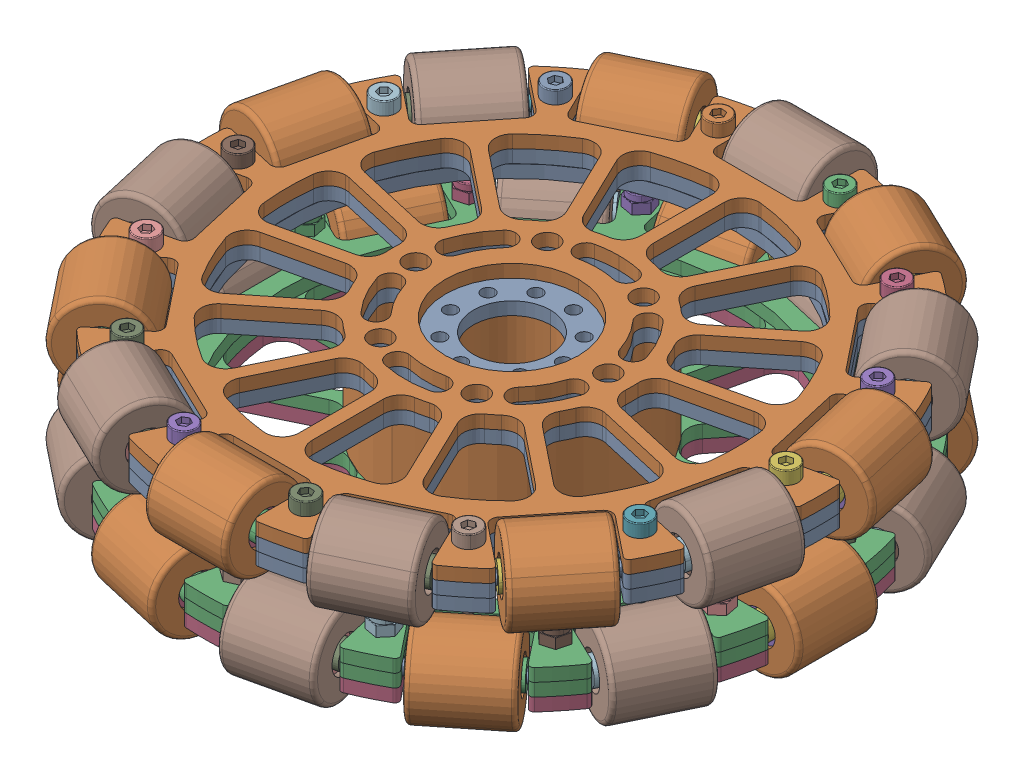
SolidWorks assembly 南京理工大学Alliance航发全向轮装配V2.STEP, configuration 默认. Lengths in mm.
Overall size (201.18 51.02 200.87).
259 component instances, 10 part files, 0 mates.
Components (placement in the parent):
- 南京理工大学Alliance航发小滚子装配.STEP-1: 南京理工大学Alliance航发小滚子装配.STEP [默认] at (-12.75 1.5 67) x (0 -0.970891 0.239524) z (0 0.239524 0.970891) size (24.07 25.5 24.07)
  - 南京理工大学Alliance销钉M3x25.5.STEP-1: 南京理工大学Alliance销钉M3x25.5.STEP [默认] at origin size (3 25.5 3)
  - 南京理工大学Alliance白色滚子.STEP-1: 南京理工大学Alliance白色滚子.STEP [默认] at (0 3.25 0) x (0.94776 0 0.318984) z (-0.318984 0 0.94776) size (19 19 19)
  - 南京理工大学Alliance垫片3x6x2.STEP-1: 南京理工大学Alliance垫片3x6x2.STEP [默认] at (0 20.85 0) size (6 2 6)
  - 南京理工大学Alliance轴承3x8x4.STEP-1: 南京理工大学Alliance轴承3x8x4.STEP [默认] at (0 16.85 0) size (8 4 8)
  - 南京理工大学Alliance轴承3x8x4.STEP-2: 南京理工大学Alliance轴承3x8x4.STEP [默认] at (0 4.65 0) size (8 4 8)
  - 南京理工大学Alliance垫片3x6x2.STEP-2: 南京理工大学Alliance垫片3x6x2.STEP [默认] at (0 2.65 0) size (6 2 6)
- 南京理工大学Alliance航发小滚子装配.STEP-2: 南京理工大学Alliance航发小滚子装配.STEP [默认] at (2.4786 -18.5 68.1573) x (-0.189674 -0.52291 -0.831017) z (0.116358 -0.852388 0.509799) size (24.07 25.5 24.07)
  - 南京理工大学Alliance销钉M3x25.5.STEP-1: 南京理工大学Alliance销钉M3x25.5.STEP [默认] at origin size (3 25.5 3)
  - 南京理工大学Alliance白色滚子.STEP-1: 南京理工大学Alliance白色滚子.STEP [默认] at (0 3.25 0) x (0.94776 0 0.318984) z (-0.318984 0 0.94776) size (19 19 19)
  - 南京理工大学Alliance垫片3x6x2.STEP-1: 南京理工大学Alliance垫片3x6x2.STEP [默认] at (0 20.85 0) size (6 2 6)
  - 南京理工大学Alliance轴承3x8x4.STEP-1: 南京理工大学Alliance轴承3x8x4.STEP [默认] at (0 16.85 0) size (8 4 8)
  - 南京理工大学Alliance轴承3x8x4.STEP-2: 南京理工大学Alliance轴承3x8x4.STEP [默认] at (0 4.65 0) size (8 4 8)
  - 南京理工大学Alliance垫片3x6x2.STEP-2: 南京理工大学Alliance垫片3x6x2.STEP [默认] at (0 2.65 0) size (6 2 6)
- 南京理工大学Alliance航发小滚子装配.STEP-3: 南京理工大学Alliance航发小滚子装配.STEP [默认] at (-27.3392 -18.5 62.483) x (0.189674 -0.52291 -0.831017) z (-0.116358 -0.852388 0.509799) size (24.07 25.5 24.07)
  - 南京理工大学Alliance销钉M3x25.5.STEP-1: 南京理工大学Alliance销钉M3x25.5.STEP [默认] at origin size (3 25.5 3)
  - 南京理工大学Alliance白色滚子.STEP-1: 南京理工大学Alliance白色滚子.STEP [默认] at (0 3.25 0) x (0.94776 0 0.318984) z (-0.318984 0 0.94776) size (19 19 19)
  - 南京理工大学Alliance垫片3x6x2.STEP-1: 南京理工大学Alliance垫片3x6x2.STEP [默认] at (0 20.85 0) size (6 2 6)
  - 南京理工大学Alliance轴承3x8x4.STEP-1: 南京理工大学Alliance轴承3x8x4.STEP [默认] at (0 16.85 0) size (8 4 8)
  - 南京理工大学Alliance轴承3x8x4.STEP-2: 南京理工大学Alliance轴承3x8x4.STEP [默认] at (0 4.65 0) size (8 4 8)
  - 南京理工大学Alliance垫片3x6x2.STEP-2: 南京理工大学Alliance垫片3x6x2.STEP [默认] at (0 2.65 0) size (6 2 6)
- 南京理工大学Alliance航发小滚子装配.STEP-4: 南京理工大学Alliance航发小滚子装配.STEP [默认] at (-51.7422 -18.5 44.4332) x (0.531455 -0.52291 -0.666424) z (-0.326029 -0.852388 0.408827) size (24.07 25.5 24.07)
  - 南京理工大学Alliance销钉M3x25.5.STEP-1: 南京理工大学Alliance销钉M3x25.5.STEP [默认] at origin size (3 25.5 3)
  - 南京理工大学Alliance白色滚子.STEP-1: 南京理工大学Alliance白色滚子.STEP [默认] at (0 3.25 0) x (0.94776 0 0.318984) z (-0.318984 0 0.94776) size (19 19 19)
  - 南京理工大学Alliance垫片3x6x2.STEP-1: 南京理工大学Alliance垫片3x6x2.STEP [默认] at (0 20.85 0) size (6 2 6)
  - 南京理工大学Alliance轴承3x8x4.STEP-1: 南京理工大学Alliance轴承3x8x4.STEP [默认] at (0 16.85 0) size (8 4 8)
  - 南京理工大学Alliance轴承3x8x4.STEP-2: 南京理工大学Alliance轴承3x8x4.STEP [默认] at (0 4.65 0) size (8 4 8)
  - 南京理工大学Alliance垫片3x6x2.STEP-2: 南京理工大学Alliance垫片3x6x2.STEP [默认] at (0 2.65 0) size (6 2 6)
- 南京理工大学Alliance航发小滚子装配.STEP-5: 南京理工大学Alliance航发小滚子装配.STEP [默认] at (-65.8969 -18.5 17.5829) x (0.767975 -0.52291 -0.369837) z (-0.471125 -0.852388 0.226882) size (24.07 25.5 24.07)
  - 南京理工大学Alliance销钉M3x25.5.STEP-1: 南京理工大学Alliance销钉M3x25.5.STEP [默认] at origin size (3 25.5 3)
  - 南京理工大学Alliance白色滚子.STEP-1: 南京理工大学Alliance白色滚子.STEP [默认] at (0 3.25 0) x (0.94776 0 0.318984) z (-0.318984 0 0.94776) size (19 19 19)
  - 南京理工大学Alliance垫片3x6x2.STEP-1: 南京理工大学Alliance垫片3x6x2.STEP [默认] at (0 20.85 0) size (6 2 6)
  - 南京理工大学Alliance轴承3x8x4.STEP-1: 南京理工大学Alliance轴承3x8x4.STEP [默认] at (0 16.85 0) size (8 4 8)
  - 南京理工大学Alliance轴承3x8x4.STEP-2: 南京理工大学Alliance轴承3x8x4.STEP [默认] at (0 4.65 0) size (8 4 8)
  - 南京理工大学Alliance垫片3x6x2.STEP-2: 南京理工大学Alliance垫片3x6x2.STEP [默认] at (0 2.65 0) size (6 2 6)
- 南京理工大学Alliance航发小滚子装配.STEP-6: 南京理工大学Alliance航发小滚子装配.STEP [默认] at (-67 -18.5 -12.75) x (0.852388 -0.52291 0) z (-0.52291 -0.852388 0) size (24.07 25.5 24.07)
  - 南京理工大学Alliance销钉M3x25.5.STEP-1: 南京理工大学Alliance销钉M3x25.5.STEP [默认] at origin size (3 25.5 3)
  - 南京理工大学Alliance白色滚子.STEP-1: 南京理工大学Alliance白色滚子.STEP [默认] at (0 3.25 0) x (0.94776 0 0.318984) z (-0.318984 0 0.94776) size (19 19 19)
  - 南京理工大学Alliance垫片3x6x2.STEP-1: 南京理工大学Alliance垫片3x6x2.STEP [默认] at (0 20.85 0) size (6 2 6)
  - 南京理工大学Alliance轴承3x8x4.STEP-1: 南京理工大学Alliance轴承3x8x4.STEP [默认] at (0 16.85 0) size (8 4 8)
  - 南京理工大学Alliance轴承3x8x4.STEP-2: 南京理工大学Alliance轴承3x8x4.STEP [默认] at (0 4.65 0) size (8 4 8)
  - 南京理工大学Alliance垫片3x6x2.STEP-2: 南京理工大学Alliance垫片3x6x2.STEP [默认] at (0 2.65 0) size (6 2 6)
- 南京理工大学Alliance航发小滚子装配.STEP-7: 南京理工大学Alliance航发小滚子装配.STEP [默认] at (-54.8329 -18.5 -40.5576) x (0.767975 -0.52291 0.369837) z (-0.471125 -0.852388 -0.226882) size (24.07 25.5 24.07)
  - 南京理工大学Alliance销钉M3x25.5.STEP-1: 南京理工大学Alliance销钉M3x25.5.STEP [默认] at origin size (3 25.5 3)
  - 南京理工大学Alliance白色滚子.STEP-1: 南京理工大学Alliance白色滚子.STEP [默认] at (0 3.25 0) x (0.94776 0 0.318984) z (-0.318984 0 0.94776) size (19 19 19)
  - 南京理工大学Alliance垫片3x6x2.STEP-1: 南京理工大学Alliance垫片3x6x2.STEP [默认] at (0 20.85 0) size (6 2 6)
  - 南京理工大学Alliance轴承3x8x4.STEP-1: 南京理工大学Alliance轴承3x8x4.STEP [默认] at (0 16.85 0) size (8 4 8)
  - 南京理工大学Alliance轴承3x8x4.STEP-2: 南京理工大学Alliance轴承3x8x4.STEP [默认] at (0 4.65 0) size (8 4 8)
  - 南京理工大学Alliance垫片3x6x2.STEP-2: 南京理工大学Alliance垫片3x6x2.STEP [默认] at (0 2.65 0) size (6 2 6)
- 南京理工大学Alliance航发小滚子装配.STEP-8: 南京理工大学Alliance航发小滚子装配.STEP [默认] at (-31.8055 -18.5 -60.3322) x (0.531455 -0.52291 0.666424) z (-0.326029 -0.852388 -0.408827) size (24.07 25.5 24.07)
  - 南京理工大学Alliance销钉M3x25.5.STEP-1: 南京理工大学Alliance销钉M3x25.5.STEP [默认] at origin size (3 25.5 3)
  - 南京理工大学Alliance白色滚子.STEP-1: 南京理工大学Alliance白色滚子.STEP [默认] at (0 3.25 0) x (0.94776 0 0.318984) z (-0.318984 0 0.94776) size (19 19 19)
  - 南京理工大学Alliance垫片3x6x2.STEP-1: 南京理工大学Alliance垫片3x6x2.STEP [默认] at (0 20.85 0) size (6 2 6)
  - 南京理工大学Alliance轴承3x8x4.STEP-1: 南京理工大学Alliance轴承3x8x4.STEP [默认] at (0 16.85 0) size (8 4 8)
  - 南京理工大学Alliance轴承3x8x4.STEP-2: 南京理工大学Alliance轴承3x8x4.STEP [默认] at (0 4.65 0) size (8 4 8)
  - 南京理工大学Alliance垫片3x6x2.STEP-2: 南京理工大学Alliance垫片3x6x2.STEP [默认] at (0 2.65 0) size (6 2 6)
- 南京理工大学Alliance航发小滚子装配.STEP-9: 南京理工大学Alliance航发小滚子装配.STEP [默认] at (-2.4786 -18.5 -68.1573) x (0.189674 -0.52291 0.831017) z (-0.116358 -0.852388 -0.509799) size (24.07 25.5 24.07)
  - 南京理工大学Alliance销钉M3x25.5.STEP-1: 南京理工大学Alliance销钉M3x25.5.STEP [默认] at origin size (3 25.5 3)
  - 南京理工大学Alliance白色滚子.STEP-1: 南京理工大学Alliance白色滚子.STEP [默认] at (0 3.25 0) x (0.94776 0 0.318984) z (-0.318984 0 0.94776) size (19 19 19)
  - 南京理工大学Alliance垫片3x6x2.STEP-1: 南京理工大学Alliance垫片3x6x2.STEP [默认] at (0 20.85 0) size (6 2 6)
  - 南京理工大学Alliance轴承3x8x4.STEP-1: 南京理工大学Alliance轴承3x8x4.STEP [默认] at (0 16.85 0) size (8 4 8)
  - 南京理工大学Alliance轴承3x8x4.STEP-2: 南京理工大学Alliance轴承3x8x4.STEP [默认] at (0 4.65 0) size (8 4 8)
  - 南京理工大学Alliance垫片3x6x2.STEP-2: 南京理工大学Alliance垫片3x6x2.STEP [默认] at (0 2.65 0) size (6 2 6)
- 南京理工大学Alliance航发小滚子装配.STEP-10: 南京理工大学Alliance航发小滚子装配.STEP [默认] at (27.3392 -18.5 -62.483) x (-0.189674 -0.52291 0.831017) z (0.116358 -0.852388 -0.509799) size (24.07 25.5 24.07)
  - 南京理工大学Alliance销钉M3x25.5.STEP-1: 南京理工大学Alliance销钉M3x25.5.STEP [默认] at origin size (3 25.5 3)
  - 南京理工大学Alliance白色滚子.STEP-1: 南京理工大学Alliance白色滚子.STEP [默认] at (0 3.25 0) x (0.94776 0 0.318984) z (-0.318984 0 0.94776) size (19 19 19)
  - 南京理工大学Alliance垫片3x6x2.STEP-1: 南京理工大学Alliance垫片3x6x2.STEP [默认] at (0 20.85 0) size (6 2 6)
  - 南京理工大学Alliance轴承3x8x4.STEP-1: 南京理工大学Alliance轴承3x8x4.STEP [默认] at (0 16.85 0) size (8 4 8)
  - 南京理工大学Alliance轴承3x8x4.STEP-2: 南京理工大学Alliance轴承3x8x4.STEP [默认] at (0 4.65 0) size (8 4 8)
  - 南京理工大学Alliance垫片3x6x2.STEP-2: 南京理工大学Alliance垫片3x6x2.STEP [默认] at (0 2.65 0) size (6 2 6)
- 南京理工大学Alliance航发小滚子装配.STEP-11: 南京理工大学Alliance航发小滚子装配.STEP [默认] at (51.7422 -18.5 -44.4332) x (-0.531455 -0.52291 0.666424) z (0.326029 -0.852388 -0.408827) size (24.07 25.5 24.07)
  - 南京理工大学Alliance销钉M3x25.5.STEP-1: 南京理工大学Alliance销钉M3x25.5.STEP [默认] at origin size (3 25.5 3)
  - 南京理工大学Alliance白色滚子.STEP-1: 南京理工大学Alliance白色滚子.STEP [默认] at (0 3.25 0) x (0.94776 0 0.318984) z (-0.318984 0 0.94776) size (19 19 19)
  - 南京理工大学Alliance垫片3x6x2.STEP-1: 南京理工大学Alliance垫片3x6x2.STEP [默认] at (0 20.85 0) size (6 2 6)
  - 南京理工大学Alliance轴承3x8x4.STEP-1: 南京理工大学Alliance轴承3x8x4.STEP [默认] at (0 16.85 0) size (8 4 8)
  - 南京理工大学Alliance轴承3x8x4.STEP-2: 南京理工大学Alliance轴承3x8x4.STEP [默认] at (0 4.65 0) size (8 4 8)
  - 南京理工大学Alliance垫片3x6x2.STEP-2: 南京理工大学Alliance垫片3x6x2.STEP [默认] at (0 2.65 0) size (6 2 6)
- 南京理工大学Alliance航发小滚子装配.STEP-12: 南京理工大学Alliance航发小滚子装配.STEP [默认] at (65.8969 -18.5 -17.5829) x (-0.767975 -0.52291 0.369837) z (0.471125 -0.852388 -0.226882) size (24.07 25.5 24.07)
  - 南京理工大学Alliance销钉M3x25.5.STEP-1: 南京理工大学Alliance销钉M3x25.5.STEP [默认] at origin size (3 25.5 3)
  - 南京理工大学Alliance白色滚子.STEP-1: 南京理工大学Alliance白色滚子.STEP [默认] at (0 3.25 0) x (0.94776 0 0.318984) z (-0.318984 0 0.94776) size (19 19 19)
  - 南京理工大学Alliance垫片3x6x2.STEP-1: 南京理工大学Alliance垫片3x6x2.STEP [默认] at (0 20.85 0) size (6 2 6)
  - 南京理工大学Alliance轴承3x8x4.STEP-1: 南京理工大学Alliance轴承3x8x4.STEP [默认] at (0 16.85 0) size (8 4 8)
  - 南京理工大学Alliance轴承3x8x4.STEP-2: 南京理工大学Alliance轴承3x8x4.STEP [默认] at (0 4.65 0) size (8 4 8)
  - 南京理工大学Alliance垫片3x6x2.STEP-2: 南京理工大学Alliance垫片3x6x2.STEP [默认] at (0 2.65 0) size (6 2 6)
- 南京理工大学Alliance航发小滚子装配.STEP-13: 南京理工大学Alliance航发小滚子装配.STEP [默认] at (67 -18.5 12.75) x (-0.852388 -0.52291 0) z (0.52291 -0.852388 0) size (24.07 25.5 24.07)
  - 南京理工大学Alliance销钉M3x25.5.STEP-1: 南京理工大学Alliance销钉M3x25.5.STEP [默认] at origin size (3 25.5 3)
  - 南京理工大学Alliance白色滚子.STEP-1: 南京理工大学Alliance白色滚子.STEP [默认] at (0 3.25 0) x (0.94776 0 0.318984) z (-0.318984 0 0.94776) size (19 19 19)
  - 南京理工大学Alliance垫片3x6x2.STEP-1: 南京理工大学Alliance垫片3x6x2.STEP [默认] at (0 20.85 0) size (6 2 6)
  - 南京理工大学Alliance轴承3x8x4.STEP-1: 南京理工大学Alliance轴承3x8x4.STEP [默认] at (0 16.85 0) size (8 4 8)
  - 南京理工大学Alliance轴承3x8x4.STEP-2: 南京理工大学Alliance轴承3x8x4.STEP [默认] at (0 4.65 0) size (8 4 8)
  - 南京理工大学Alliance垫片3x6x2.STEP-2: 南京理工大学Alliance垫片3x6x2.STEP [默认] at (0 2.65 0) size (6 2 6)
- 南京理工大学Alliance航发小滚子装配.STEP-14: 南京理工大学Alliance航发小滚子装配.STEP [默认] at (54.8329 -18.5 40.5576) x (-0.767975 -0.52291 -0.369837) z (0.471125 -0.852388 0.226882) size (24.07 25.5 24.07)
  - 南京理工大学Alliance销钉M3x25.5.STEP-1: 南京理工大学Alliance销钉M3x25.5.STEP [默认] at origin size (3 25.5 3)
  - 南京理工大学Alliance白色滚子.STEP-1: 南京理工大学Alliance白色滚子.STEP [默认] at (0 3.25 0) x (0.94776 0 0.318984) z (-0.318984 0 0.94776) size (19 19 19)
  - 南京理工大学Alliance垫片3x6x2.STEP-1: 南京理工大学Alliance垫片3x6x2.STEP [默认] at (0 20.85 0) size (6 2 6)
  - 南京理工大学Alliance轴承3x8x4.STEP-1: 南京理工大学Alliance轴承3x8x4.STEP [默认] at (0 16.85 0) size (8 4 8)
  - 南京理工大学Alliance轴承3x8x4.STEP-2: 南京理工大学Alliance轴承3x8x4.STEP [默认] at (0 4.65 0) size (8 4 8)
  - 南京理工大学Alliance垫片3x6x2.STEP-2: 南京理工大学Alliance垫片3x6x2.STEP [默认] at (0 2.65 0) size (6 2 6)
- 南京理工大学Alliance航发小滚子装配.STEP-15: 南京理工大学Alliance航发小滚子装配.STEP [默认] at (31.8055 -18.5 60.3322) x (-0.531455 -0.52291 -0.666424) z (0.326029 -0.852388 0.408827) size (24.07 25.5 24.07)
  - 南京理工大学Alliance销钉M3x25.5.STEP-1: 南京理工大学Alliance销钉M3x25.5.STEP [默认] at origin size (3 25.5 3)
  - 南京理工大学Alliance白色滚子.STEP-1: 南京理工大学Alliance白色滚子.STEP [默认] at (0 3.25 0) x (0.94776 0 0.318984) z (-0.318984 0 0.94776) size (19 19 19)
  - 南京理工大学Alliance垫片3x6x2.STEP-1: 南京理工大学Alliance垫片3x6x2.STEP [默认] at (0 20.85 0) size (6 2 6)
  - 南京理工大学Alliance轴承3x8x4.STEP-1: 南京理工大学Alliance轴承3x8x4.STEP [默认] at (0 16.85 0) size (8 4 8)
  - 南京理工大学Alliance轴承3x8x4.STEP-2: 南京理工大学Alliance轴承3x8x4.STEP [默认] at (0 4.65 0) size (8 4 8)
  - 南京理工大学Alliance垫片3x6x2.STEP-2: 南京理工大学Alliance垫片3x6x2.STEP [默认] at (0 2.65 0) size (6 2 6)
- 南京理工大学Alliance航发小滚子装配.STEP-16: 南京理工大学Alliance航发小滚子装配.STEP [默认] at (-40.5576 1.5 54.8329) x (-0.103925 -0.970891 0.215803) z (-0.421254 0.239524 0.874742) size (24.07 25.5 24.07)
  - 南京理工大学Alliance销钉M3x25.5.STEP-1: 南京理工大学Alliance销钉M3x25.5.STEP [默认] at origin size (3 25.5 3)
  - 南京理工大学Alliance白色滚子.STEP-1: 南京理工大学Alliance白色滚子.STEP [默认] at (0 3.25 0) x (0.94776 0 0.318984) z (-0.318984 0 0.94776) size (19 19 19)
  - 南京理工大学Alliance垫片3x6x2.STEP-1: 南京理工大学Alliance垫片3x6x2.STEP [默认] at (0 20.85 0) size (6 2 6)
  - 南京理工大学Alliance轴承3x8x4.STEP-1: 南京理工大学Alliance轴承3x8x4.STEP [默认] at (0 16.85 0) size (8 4 8)
  - 南京理工大学Alliance轴承3x8x4.STEP-2: 南京理工大学Alliance轴承3x8x4.STEP [默认] at (0 4.65 0) size (8 4 8)
  - 南京理工大学Alliance垫片3x6x2.STEP-2: 南京理工大学Alliance垫片3x6x2.STEP [默认] at (0 2.65 0) size (6 2 6)
- 南京理工大学Alliance航发小滚子装配.STEP-17: 南京理工大学Alliance航发小滚子装配.STEP [默认] at (-60.3322 1.5 31.8055) x (-0.187267 -0.970891 0.14934) z (-0.759073 0.239524 0.60534) size (24.07 25.5 24.07)
  - 南京理工大学Alliance销钉M3x25.5.STEP-1: 南京理工大学Alliance销钉M3x25.5.STEP [默认] at origin size (3 25.5 3)
  - 南京理工大学Alliance白色滚子.STEP-1: 南京理工大学Alliance白色滚子.STEP [默认] at (0 3.25 0) x (0.94776 0 0.318984) z (-0.318984 0 0.94776) size (19 19 19)
  - 南京理工大学Alliance垫片3x6x2.STEP-1: 南京理工大学Alliance垫片3x6x2.STEP [默认] at (0 20.85 0) size (6 2 6)
  - 南京理工大学Alliance轴承3x8x4.STEP-1: 南京理工大学Alliance轴承3x8x4.STEP [默认] at (0 16.85 0) size (8 4 8)
  - 南京理工大学Alliance轴承3x8x4.STEP-2: 南京理工大学Alliance轴承3x8x4.STEP [默认] at (0 4.65 0) size (8 4 8)
  - 南京理工大学Alliance垫片3x6x2.STEP-2: 南京理工大学Alliance垫片3x6x2.STEP [默认] at (0 2.65 0) size (6 2 6)
- 南京理工大学Alliance航发小滚子装配.STEP-18: 南京理工大学Alliance航发小滚子装配.STEP [默认] at (-68.1573 1.5 2.4786) x (-0.233518 -0.970891 0.053299) z (-0.946548 0.239524 0.216043) size (24.07 25.5 24.07)
  - 南京理工大学Alliance销钉M3x25.5.STEP-1: 南京理工大学Alliance销钉M3x25.5.STEP [默认] at origin size (3 25.5 3)
  - 南京理工大学Alliance白色滚子.STEP-1: 南京理工大学Alliance白色滚子.STEP [默认] at (0 3.25 0) x (0.94776 0 0.318984) z (-0.318984 0 0.94776) size (19 19 19)
  - 南京理工大学Alliance垫片3x6x2.STEP-1: 南京理工大学Alliance垫片3x6x2.STEP [默认] at (0 20.85 0) size (6 2 6)
  - 南京理工大学Alliance轴承3x8x4.STEP-1: 南京理工大学Alliance轴承3x8x4.STEP [默认] at (0 16.85 0) size (8 4 8)
  - 南京理工大学Alliance轴承3x8x4.STEP-2: 南京理工大学Alliance轴承3x8x4.STEP [默认] at (0 4.65 0) size (8 4 8)
  - 南京理工大学Alliance垫片3x6x2.STEP-2: 南京理工大学Alliance垫片3x6x2.STEP [默认] at (0 2.65 0) size (6 2 6)
- 南京理工大学Alliance航发小滚子装配.STEP-19: 南京理工大学Alliance航发小滚子装配.STEP [默认] at (-62.483 1.5 -27.3392) x (-0.233518 -0.970891 -0.053299) z (-0.946548 0.239524 -0.216043) size (24.07 25.5 24.07)
  - 南京理工大学Alliance销钉M3x25.5.STEP-1: 南京理工大学Alliance销钉M3x25.5.STEP [默认] at origin size (3 25.5 3)
  - 南京理工大学Alliance白色滚子.STEP-1: 南京理工大学Alliance白色滚子.STEP [默认] at (0 3.25 0) x (0.94776 0 0.318984) z (-0.318984 0 0.94776) size (19 19 19)
  - 南京理工大学Alliance垫片3x6x2.STEP-1: 南京理工大学Alliance垫片3x6x2.STEP [默认] at (0 20.85 0) size (6 2 6)
  - 南京理工大学Alliance轴承3x8x4.STEP-1: 南京理工大学Alliance轴承3x8x4.STEP [默认] at (0 16.85 0) size (8 4 8)
  - 南京理工大学Alliance轴承3x8x4.STEP-2: 南京理工大学Alliance轴承3x8x4.STEP [默认] at (0 4.65 0) size (8 4 8)
  - 南京理工大学Alliance垫片3x6x2.STEP-2: 南京理工大学Alliance垫片3x6x2.STEP [默认] at (0 2.65 0) size (6 2 6)
- 南京理工大学Alliance航发小滚子装配.STEP-20: 南京理工大学Alliance航发小滚子装配.STEP [默认] at (-44.4332 1.5 -51.7422) x (-0.187267 -0.970891 -0.14934) z (-0.759073 0.239524 -0.60534) size (24.07 25.5 24.07)
  - 南京理工大学Alliance销钉M3x25.5.STEP-1: 南京理工大学Alliance销钉M3x25.5.STEP [默认] at origin size (3 25.5 3)
  - 南京理工大学Alliance白色滚子.STEP-1: 南京理工大学Alliance白色滚子.STEP [默认] at (0 3.25 0) x (0.94776 0 0.318984) z (-0.318984 0 0.94776) size (19 19 19)
  - 南京理工大学Alliance垫片3x6x2.STEP-1: 南京理工大学Alliance垫片3x6x2.STEP [默认] at (0 20.85 0) size (6 2 6)
  - 南京理工大学Alliance轴承3x8x4.STEP-1: 南京理工大学Alliance轴承3x8x4.STEP [默认] at (0 16.85 0) size (8 4 8)
  - 南京理工大学Alliance轴承3x8x4.STEP-2: 南京理工大学Alliance轴承3x8x4.STEP [默认] at (0 4.65 0) size (8 4 8)
  - 南京理工大学Alliance垫片3x6x2.STEP-2: 南京理工大学Alliance垫片3x6x2.STEP [默认] at (0 2.65 0) size (6 2 6)
- 南京理工大学Alliance航发小滚子装配.STEP-21: 南京理工大学Alliance航发小滚子装配.STEP [默认] at (-17.5829 1.5 -65.8969) x (-0.103925 -0.970891 -0.215803) z (-0.421254 0.239524 -0.874742) size (24.07 25.5 24.07)
  - 南京理工大学Alliance销钉M3x25.5.STEP-1: 南京理工大学Alliance销钉M3x25.5.STEP [默认] at origin size (3 25.5 3)
  - 南京理工大学Alliance白色滚子.STEP-1: 南京理工大学Alliance白色滚子.STEP [默认] at (0 3.25 0) x (0.94776 0 0.318984) z (-0.318984 0 0.94776) size (19 19 19)
  - 南京理工大学Alliance垫片3x6x2.STEP-1: 南京理工大学Alliance垫片3x6x2.STEP [默认] at (0 20.85 0) size (6 2 6)
  - 南京理工大学Alliance轴承3x8x4.STEP-1: 南京理工大学Alliance轴承3x8x4.STEP [默认] at (0 16.85 0) size (8 4 8)
  - 南京理工大学Alliance轴承3x8x4.STEP-2: 南京理工大学Alliance轴承3x8x4.STEP [默认] at (0 4.65 0) size (8 4 8)
  - 南京理工大学Alliance垫片3x6x2.STEP-2: 南京理工大学Alliance垫片3x6x2.STEP [默认] at (0 2.65 0) size (6 2 6)
- 南京理工大学Alliance航发小滚子装配.STEP-22: 南京理工大学Alliance航发小滚子装配.STEP [默认] at (12.75 1.5 -67) x (0 -0.970891 -0.239524) z (0 0.239524 -0.970891) size (24.07 25.5 24.07)
  - 南京理工大学Alliance销钉M3x25.5.STEP-1: 南京理工大学Alliance销钉M3x25.5.STEP [默认] at origin size (3 25.5 3)
  - 南京理工大学Alliance白色滚子.STEP-1: 南京理工大学Alliance白色滚子.STEP [默认] at (0 3.25 0) x (0.94776 0 0.318984) z (-0.318984 0 0.94776) size (19 19 19)
  - 南京理工大学Alliance垫片3x6x2.STEP-1: 南京理工大学Alliance垫片3x6x2.STEP [默认] at (0 20.85 0) size (6 2 6)
  - 南京理工大学Alliance轴承3x8x4.STEP-1: 南京理工大学Alliance轴承3x8x4.STEP [默认] at (0 16.85 0) size (8 4 8)
  - 南京理工大学Alliance轴承3x8x4.STEP-2: 南京理工大学Alliance轴承3x8x4.STEP [默认] at (0 4.65 0) size (8 4 8)
  - 南京理工大学Alliance垫片3x6x2.STEP-2: 南京理工大学Alliance垫片3x6x2.STEP [默认] at (0 2.65 0) size (6 2 6)
- 南京理工大学Alliance航发小滚子装配.STEP-23: 南京理工大学Alliance航发小滚子装配.STEP [默认] at (40.5576 1.5 -54.8329) x (0.103925 -0.970891 -0.215803) z (0.421254 0.239524 -0.874742) size (24.07 25.5 24.07)
  - 南京理工大学Alliance销钉M3x25.5.STEP-1: 南京理工大学Alliance销钉M3x25.5.STEP [默认] at origin size (3 25.5 3)
  - 南京理工大学Alliance白色滚子.STEP-1: 南京理工大学Alliance白色滚子.STEP [默认] at (0 3.25 0) x (0.94776 0 0.318984) z (-0.318984 0 0.94776) size (19 19 19)
  - 南京理工大学Alliance垫片3x6x2.STEP-1: 南京理工大学Alliance垫片3x6x2.STEP [默认] at (0 20.85 0) size (6 2 6)
  - 南京理工大学Alliance轴承3x8x4.STEP-1: 南京理工大学Alliance轴承3x8x4.STEP [默认] at (0 16.85 0) size (8 4 8)
  - 南京理工大学Alliance轴承3x8x4.STEP-2: 南京理工大学Alliance轴承3x8x4.STEP [默认] at (0 4.65 0) size (8 4 8)
  - 南京理工大学Alliance垫片3x6x2.STEP-2: 南京理工大学Alliance垫片3x6x2.STEP [默认] at (0 2.65 0) size (6 2 6)
- 南京理工大学Alliance航发小滚子装配.STEP-24: 南京理工大学Alliance航发小滚子装配.STEP [默认] at (60.3322 1.5 -31.8055) x (0.187267 -0.970891 -0.14934) z (0.759073 0.239524 -0.60534) size (24.07 25.5 24.07)
  - 南京理工大学Alliance销钉M3x25.5.STEP-1: 南京理工大学Alliance销钉M3x25.5.STEP [默认] at origin size (3 25.5 3)
  - 南京理工大学Alliance白色滚子.STEP-1: 南京理工大学Alliance白色滚子.STEP [默认] at (0 3.25 0) x (0.94776 0 0.318984) z (-0.318984 0 0.94776) size (19 19 19)
  - 南京理工大学Alliance垫片3x6x2.STEP-1: 南京理工大学Alliance垫片3x6x2.STEP [默认] at (0 20.85 0) size (6 2 6)
  - 南京理工大学Alliance轴承3x8x4.STEP-1: 南京理工大学Alliance轴承3x8x4.STEP [默认] at (0 16.85 0) size (8 4 8)
  - 南京理工大学Alliance轴承3x8x4.STEP-2: 南京理工大学Alliance轴承3x8x4.STEP [默认] at (0 4.65 0) size (8 4 8)
  - 南京理工大学Alliance垫片3x6x2.STEP-2: 南京理工大学Alliance垫片3x6x2.STEP [默认] at (0 2.65 0) size (6 2 6)
- 南京理工大学Alliance航发小滚子装配.STEP-25: 南京理工大学Alliance航发小滚子装配.STEP [默认] at (68.1573 1.5 -2.4786) x (0.233518 -0.970891 -0.053299) z (0.946548 0.239524 -0.216043) size (24.07 25.5 24.07)
  - 南京理工大学Alliance销钉M3x25.5.STEP-1: 南京理工大学Alliance销钉M3x25.5.STEP [默认] at origin size (3 25.5 3)
  - 南京理工大学Alliance白色滚子.STEP-1: 南京理工大学Alliance白色滚子.STEP [默认] at (0 3.25 0) x (0.94776 0 0.318984) z (-0.318984 0 0.94776) size (19 19 19)
  - 南京理工大学Alliance垫片3x6x2.STEP-1: 南京理工大学Alliance垫片3x6x2.STEP [默认] at (0 20.85 0) size (6 2 6)
  - 南京理工大学Alliance轴承3x8x4.STEP-1: 南京理工大学Alliance轴承3x8x4.STEP [默认] at (0 16.85 0) size (8 4 8)
  - 南京理工大学Alliance轴承3x8x4.STEP-2: 南京理工大学Alliance轴承3x8x4.STEP [默认] at (0 4.65 0) size (8 4 8)
  - 南京理工大学Alliance垫片3x6x2.STEP-2: 南京理工大学Alliance垫片3x6x2.STEP [默认] at (0 2.65 0) size (6 2 6)
- 南京理工大学Alliance航发小滚子装配.STEP-26: 南京理工大学Alliance航发小滚子装配.STEP [默认] at (62.483 1.5 27.3392) x (0.233518 -0.970891 0.053299) z (0.946548 0.239524 0.216043) size (24.07 25.5 24.07)
  - 南京理工大学Alliance销钉M3x25.5.STEP-1: 南京理工大学Alliance销钉M3x25.5.STEP [默认] at origin size (3 25.5 3)
  - 南京理工大学Alliance白色滚子.STEP-1: 南京理工大学Alliance白色滚子.STEP [默认] at (0 3.25 0) x (0.94776 0 0.318984) z (-0.318984 0 0.94776) size (19 19 19)
  - 南京理工大学Alliance垫片3x6x2.STEP-1: 南京理工大学Alliance垫片3x6x2.STEP [默认] at (0 20.85 0) size (6 2 6)
  - 南京理工大学Alliance轴承3x8x4.STEP-1: 南京理工大学Alliance轴承3x8x4.STEP [默认] at (0 16.85 0) size (8 4 8)
  - 南京理工大学Alliance轴承3x8x4.STEP-2: 南京理工大学Alliance轴承3x8x4.STEP [默认] at (0 4.65 0) size (8 4 8)
  - 南京理工大学Alliance垫片3x6x2.STEP-2: 南京理工大学Alliance垫片3x6x2.STEP [默认] at (0 2.65 0) size (6 2 6)
- 南京理工大学Alliance航发小滚子装配.STEP-27: 南京理工大学Alliance航发小滚子装配.STEP [默认] at (44.4332 1.5 51.7422) x (0.187267 -0.970891 0.14934) z (0.759073 0.239524 0.60534) size (24.07 25.5 24.07)
  - 南京理工大学Alliance销钉M3x25.5.STEP-1: 南京理工大学Alliance销钉M3x25.5.STEP [默认] at origin size (3 25.5 3)
  - 南京理工大学Alliance白色滚子.STEP-1: 南京理工大学Alliance白色滚子.STEP [默认] at (0 3.25 0) x (0.94776 0 0.318984) z (-0.318984 0 0.94776) size (19 19 19)
  - 南京理工大学Alliance垫片3x6x2.STEP-1: 南京理工大学Alliance垫片3x6x2.STEP [默认] at (0 20.85 0) size (6 2 6)
  - 南京理工大学Alliance轴承3x8x4.STEP-1: 南京理工大学Alliance轴承3x8x4.STEP [默认] at (0 16.85 0) size (8 4 8)
  - 南京理工大学Alliance轴承3x8x4.STEP-2: 南京理工大学Alliance轴承3x8x4.STEP [默认] at (0 4.65 0) size (8 4 8)
  - 南京理工大学Alliance垫片3x6x2.STEP-2: 南京理工大学Alliance垫片3x6x2.STEP [默认] at (0 2.65 0) size (6 2 6)
- 南京理工大学Alliance航发小滚子装配.STEP-28: 南京理工大学Alliance航发小滚子装配.STEP [默认] at (17.5829 1.5 65.8969) x (0.103925 -0.970891 0.215803) z (0.421254 0.239524 0.874742) size (24.07 25.5 24.07)
  - 南京理工大学Alliance销钉M3x25.5.STEP-1: 南京理工大学Alliance销钉M3x25.5.STEP [默认] at origin size (3 25.5 3)
  - 南京理工大学Alliance白色滚子.STEP-1: 南京理工大学Alliance白色滚子.STEP [默认] at (0 3.25 0) x (0.94776 0 0.318984) z (-0.318984 0 0.94776) size (19 19 19)
  - 南京理工大学Alliance垫片3x6x2.STEP-1: 南京理工大学Alliance垫片3x6x2.STEP [默认] at (0 20.85 0) size (6 2 6)
  - 南京理工大学Alliance轴承3x8x4.STEP-1: 南京理工大学Alliance轴承3x8x4.STEP [默认] at (0 16.85 0) size (8 4 8)
  - 南京理工大学Alliance轴承3x8x4.STEP-2: 南京理工大学Alliance轴承3x8x4.STEP [默认] at (0 4.65 0) size (8 4 8)
  - 南京理工大学Alliance垫片3x6x2.STEP-2: 南京理工大学Alliance垫片3x6x2.STEP [默认] at (0 2.65 0) size (6 2 6)
- 南京理工大学Alliance航发全向轮中间夹板.STEP-1: 南京理工大学Alliance航发全向轮中间夹板.STEP [默认] at origin size (144 3 142.09)
- 南京理工大学Alliance航发全向轮外板.STEP-1: 南京理工大学Alliance航发全向轮外板.STEP [默认] at (0 3 0) size (144 3 142.09)
- 南京理工大学Alliance航发全向轮中间夹板.STEP-2: 南京理工大学Alliance航发全向轮中间夹板.STEP [默认] at (0 -20 0) x (0.781831 0 0.62349) z (-0.62349 0 0.781831) size (144 3 142.09)
- 南京理工大学Alliance航发全向轮外板.STEP-2: 南京理工大学Alliance航发全向轮外板.STEP [默认] at (0 -23 0) x (0.781831 0 0.62349) z (-0.62349 0 0.781831) size (144 3 142.09)
- 南京理工大学AllianceM3螺栓_M3-14.STEP-1: 南京理工大学AllianceM3螺栓_M3-14.STEP [默认] at (-14.2413 9 62.3954) x (0 -1 0) z (0.007101 0 0.999975) size (17 5.68 5.68)
- 南京理工大学Alliance防松螺母_M3防松螺母.STEP-1: 南京理工大学Alliance防松螺母_M3防松螺母.STEP [默认] at (-14.2413 -3 62.3954) x (0.799377 0 0.60083) z (0.60083 0 -0.799377) size (6.35 3.9 5.5)
- 南京理工大学AllianceM3螺栓_M3-14.STEP-2: 南京理工大学AllianceM3螺栓_M3-14.STEP [默认] at (0 -26 64) x (0 1 0) z (-0.546878 0 0.837212) size (17 5.68 5.68)
- 南京理工大学Alliance防松螺母_M3防松螺母.STEP-2: 南京理工大学Alliance防松螺母_M3防松螺母.STEP [默认] at (0 -14 64) x (-0.912708 0 0.408613) z (-0.408613 0 -0.912708) size (6.35 3.9 5.5)
- 南京理工大学AllianceM3螺栓_M3-14.STEP-3: 南京理工大学AllianceM3螺栓_M3-14.STEP [默认] at (-39.9033 9 50.0372) x (0 -1 0) z (-0.427475 0 0.904027) size (17 5.68 5.68)
- 南京理工大学AllianceM3螺栓_M3-14.STEP-4: 南京理工大学AllianceM3螺栓_M3-14.STEP [默认] at (-57.662 9 27.7686) x (0 -1 0) z (-0.777384 0 0.629026) size (17 5.68 5.68)
- 南京理工大学AllianceM3螺栓_M3-14.STEP-5: 南京理工大学AllianceM3螺栓_M3-14.STEP [默认] at (-64 9 0) x (0 -1 0) z (-0.973323 0 0.229439) size (17 5.68 5.68)
- 南京理工大学AllianceM3螺栓_M3-14.STEP-6: 南京理工大学AllianceM3螺栓_M3-14.STEP [默认] at (-57.662 9 -27.7686) x (0 -1 0) z (-0.976484 0 -0.215592) size (17 5.68 5.68)
- 南京理工大学AllianceM3螺栓_M3-14.STEP-7: 南京理工大学AllianceM3螺栓_M3-14.STEP [默认] at (-39.9033 9 -50.0372) x (0 -1 0) z (-0.786239 0 -0.617922) size (17 5.68 5.68)
- 南京理工大学AllianceM3螺栓_M3-14.STEP-8: 南京理工大学AllianceM3螺栓_M3-14.STEP [默认] at (-14.2413 9 -62.3954) x (0 -1 0) z (-0.440271 0 -0.897865) size (17 5.68 5.68)
- 南京理工大学AllianceM3螺栓_M3-14.STEP-9: 南京理工大学AllianceM3螺栓_M3-14.STEP [默认] at (14.2413 9 -62.3954) x (0 -1 0) z (-0.007101 0 -0.999975) size (17 5.68 5.68)
- 南京理工大学AllianceM3螺栓_M3-14.STEP-10: 南京理工大学AllianceM3螺栓_M3-14.STEP [默认] at (39.9033 9 -50.0372) x (0 -1 0) z (0.427475 0 -0.904027) size (17 5.68 5.68)
- 南京理工大学AllianceM3螺栓_M3-14.STEP-11: 南京理工大学AllianceM3螺栓_M3-14.STEP [默认] at (57.662 9 -27.7686) x (0 -1 0) z (0.777384 0 -0.629026) size (17 5.68 5.68)
- 南京理工大学AllianceM3螺栓_M3-14.STEP-12: 南京理工大学AllianceM3螺栓_M3-14.STEP [默认] at (64 9 0) x (0 -1 0) z (0.973323 0 -0.229439) size (17 5.68 5.68)
- 南京理工大学AllianceM3螺栓_M3-14.STEP-13: 南京理工大学AllianceM3螺栓_M3-14.STEP [默认] at (57.662 9 27.7686) x (0 -1 0) z (0.976484 0 0.215592) size (17 5.68 5.68)
- 南京理工大学AllianceM3螺栓_M3-14.STEP-14: 南京理工大学AllianceM3螺栓_M3-14.STEP [默认] at (39.9033 9 50.0372) x (0 -1 0) z (0.786239 0 0.617922) size (17 5.68 5.68)
- 南京理工大学AllianceM3螺栓_M3-14.STEP-15: 南京理工大学AllianceM3螺栓_M3-14.STEP [默认] at (14.2413 9 62.3954) x (0 -1 0) z (0.440271 0 0.897865) size (17 5.68 5.68)
- 南京理工大学Alliance防松螺母_M3防松螺母.STEP-3: 南京理工大学Alliance防松螺母_M3防松螺母.STEP [默认] at (-39.9033 -3 50.0372) x (0.459524 0 0.888166) z (0.888166 0 -0.459524) size (6.35 3.9 5.5)
- 南京理工大学Alliance防松螺母_M3防松螺母.STEP-4: 南京理工大学Alliance防松螺母_M3防松螺母.STEP [默认] at (-57.662 -3 27.7686) x (0.028656 0 0.999589) z (0.999589 0 -0.028656) size (6.35 3.9 5.5)
- 南京理工大学Alliance防松螺母_M3防松螺母.STEP-5: 南京理工大学Alliance防松螺母_M3防松螺母.STEP [默认] at (-64 -3 0) x (-0.407888 0 0.913032) z (0.913032 0 0.407888) size (6.35 3.9 5.5)
- 南京理工大学Alliance防松螺母_M3防松螺母.STEP-6: 南京理工大学Alliance防松螺母_M3防松螺母.STEP [默认] at (-57.662 -3 -27.7686) x (-0.763644 0 0.645638) z (0.645638 0 0.763644) size (6.35 3.9 5.5)
- 南京理工大学Alliance防松螺母_M3防松螺母.STEP-7: 南京理工大学Alliance防松螺母_M3防松螺母.STEP [默认] at (-39.9033 -3 -50.0372) x (-0.968151 0 0.250367) z (0.250367 0 0.968151) size (6.35 3.9 5.5)
- 南京理工大学Alliance防松螺母_M3防松螺母.STEP-8: 南京理工大学Alliance防松螺母_M3防松螺母.STEP [默认] at (-14.2413 -3 -62.3954) x (-0.980904 0 -0.194492) z (-0.194492 0 0.980904) size (6.35 3.9 5.5)
- 南京理工大学Alliance防松螺母_M3防松螺母.STEP-9: 南京理工大学Alliance防松螺母_M3防松螺母.STEP [默认] at (14.2413 -3 -62.3954) x (-0.799377 0 -0.60083) z (-0.60083 0 0.799377) size (6.35 3.9 5.5)
- 南京理工大学Alliance防松螺母_M3防松螺母.STEP-10: 南京理工大学Alliance防松螺母_M3防松螺母.STEP [默认] at (39.9033 -3 -50.0372) x (-0.459524 0 -0.888166) z (-0.888166 0 0.459524) size (6.35 3.9 5.5)
- 南京理工大学Alliance防松螺母_M3防松螺母.STEP-11: 南京理工大学Alliance防松螺母_M3防松螺母.STEP [默认] at (57.662 -3 -27.7686) x (-0.028656 0 -0.999589) z (-0.999589 0 0.028656) size (6.35 3.9 5.5)
- 南京理工大学Alliance防松螺母_M3防松螺母.STEP-12: 南京理工大学Alliance防松螺母_M3防松螺母.STEP [默认] at (64 -3 0) x (0.407888 0 -0.913032) z (-0.913032 0 -0.407888) size (6.35 3.9 5.5)
- 南京理工大学Alliance防松螺母_M3防松螺母.STEP-13: 南京理工大学Alliance防松螺母_M3防松螺母.STEP [默认] at (57.662 -3 27.7686) x (0.763644 0 -0.645638) z (-0.645638 0 -0.763644) size (6.35 3.9 5.5)
- 南京理工大学Alliance防松螺母_M3防松螺母.STEP-14: 南京理工大学Alliance防松螺母_M3防松螺母.STEP [默认] at (39.9033 -3 50.0372) x (0.968151 0 -0.250367) z (-0.250367 0 -0.968151) size (6.35 3.9 5.5)
- 南京理工大学Alliance防松螺母_M3防松螺母.STEP-15: 南京理工大学Alliance防松螺母_M3防松螺母.STEP [默认] at (14.2413 -3 62.3954) x (0.980904 0 0.194492) z (0.194492 0 -0.980904) size (6.35 3.9 5.5)
- 南京理工大学AllianceM3螺栓_M3-14.STEP-16: 南京理工大学AllianceM3螺栓_M3-14.STEP [默认] at (-27.7686 -26 57.662) x (0 1 0) z (-0.855973 0 0.51702) size (17 5.68 5.68)
- 南京理工大学AllianceM3螺栓_M3-14.STEP-17: 南京理工大学AllianceM3螺栓_M3-14.STEP [默认] at (-50.0372 -26 39.9033) x (0 1 0) z (-0.995532 0 0.094427) size (17 5.68 5.68)
- 南京理工大学AllianceM3螺栓_M3-14.STEP-18: 南京理工大学AllianceM3螺栓_M3-14.STEP [默认] at (-62.3954 -26 14.2413) x (0 1 0) z (-0.937913 0 -0.34687) size (17 5.68 5.68)
- 南京理工大学AllianceM3螺栓_M3-14.STEP-19: 南京理工大学AllianceM3螺栓_M3-14.STEP [默认] at (-62.3954 -26 -14.2413) x (0 1 0) z (-0.69453 0 -0.719464) size (17 5.68 5.68)
- 南京理工大学AllianceM3螺栓_M3-14.STEP-20: 南京理工大学AllianceM3螺栓_M3-14.STEP [默认] at (-50.0372 -26 -39.9033) x (0 1 0) z (-0.313586 0 -0.94956) size (17 5.68 5.68)
- 南京理工大学AllianceM3螺栓_M3-14.STEP-21: 南京理工大学AllianceM3螺栓_M3-14.STEP [默认] at (-27.7686 -26 -57.662) x (0 1 0) z (0.129468 0 -0.991584) size (17 5.68 5.68)
- 南京理工大学AllianceM3螺栓_M3-14.STEP-22: 南京理工大学AllianceM3螺栓_M3-14.STEP [默认] at (0 -26 -64) x (0 1 0) z (0.546878 0 -0.837212) size (17 5.68 5.68)
- 南京理工大学AllianceM3螺栓_M3-14.STEP-23: 南京理工大学AllianceM3螺栓_M3-14.STEP [默认] at (27.7686 -26 -57.662) x (0 1 0) z (0.855973 0 -0.51702) size (17 5.68 5.68)
- 南京理工大学AllianceM3螺栓_M3-14.STEP-24: 南京理工大学AllianceM3螺栓_M3-14.STEP [默认] at (50.0372 -26 -39.9033) x (0 1 0) z (0.995532 0 -0.094427) size (17 5.68 5.68)
- 南京理工大学AllianceM3螺栓_M3-14.STEP-25: 南京理工大学AllianceM3螺栓_M3-14.STEP [默认] at (62.3954 -26 -14.2413) x (0 1 0) z (0.937913 0 0.34687) size (17 5.68 5.68)
- 南京理工大学AllianceM3螺栓_M3-14.STEP-26: 南京理工大学AllianceM3螺栓_M3-14.STEP [默认] at (62.3954 -26 14.2413) x (0 1 0) z (0.69453 0 0.719464) size (17 5.68 5.68)
- 南京理工大学AllianceM3螺栓_M3-14.STEP-27: 南京理工大学AllianceM3螺栓_M3-14.STEP [默认] at (50.0372 -26 39.9033) x (0 1 0) z (0.313586 0 0.94956) size (17 5.68 5.68)
- 南京理工大学AllianceM3螺栓_M3-14.STEP-28: 南京理工大学AllianceM3螺栓_M3-14.STEP [默认] at (27.7686 -26 57.662) x (0 1 0) z (-0.129468 0 0.991584) size (17 5.68 5.68)
- 南京理工大学Alliance防松螺母_M3防松螺母.STEP-16: 南京理工大学Alliance防松螺母_M3防松螺母.STEP [默认] at (-27.7686 -14 57.662) x (-0.999612 0 -0.027861) z (0.027861 0 -0.999612) size (6.35 3.9 5.5)
- 南京理工大学Alliance防松螺母_M3防松螺母.STEP-17: 南京理工大学Alliance防松螺母_M3防松螺母.STEP [默认] at (-50.0372 -14 39.9033) x (-0.888531 0 -0.458817) z (0.458817 0 -0.888531) size (6.35 3.9 5.5)
- 南京理工大学Alliance防松螺母_M3防松螺母.STEP-18: 南京理工大学Alliance防松螺母_M3防松螺母.STEP [默认] at (-62.3954 -14 14.2413) x (-0.601465 0 -0.798899) z (0.798899 0 -0.601465) size (6.35 3.9 5.5)
- 南京理工大学Alliance防松螺母_M3防松螺母.STEP-19: 南京理工大学Alliance防松螺母_M3防松螺母.STEP [默认] at (-62.3954 -14 -14.2413) x (-0.195272 0 -0.980749) z (0.980749 0 -0.195272) size (6.35 3.9 5.5)
- 南京理工大学Alliance防松螺母_M3防松螺母.STEP-20: 南京理工大学Alliance防松螺母_M3防松螺母.STEP [默认] at (-50.0372 -14 -39.9033) x (0.249597 0 -0.96835) z (0.96835 0 0.249597) size (6.35 3.9 5.5)
- 南京理工大学Alliance防松螺母_M3防松螺母.STEP-21: 南京理工大学Alliance防松螺母_M3防松螺母.STEP [默认] at (-27.7686 -14 -57.662) x (0.64503 0 -0.764157) z (0.764157 0 0.64503) size (6.35 3.9 5.5)
- 南京理工大学Alliance防松螺母_M3防松螺母.STEP-22: 南京理工大学Alliance防松螺母_M3防松螺母.STEP [默认] at (0 -14 -64) x (0.912708 0 -0.408613) z (0.408613 0 0.912708) size (6.35 3.9 5.5)
- 南京理工大学Alliance防松螺母_M3防松螺母.STEP-23: 南京理工大学Alliance防松螺母_M3防松螺母.STEP [默认] at (27.7686 -14 -57.662) x (0.999612 0 0.027861) z (-0.027861 0 0.999612) size (6.35 3.9 5.5)
- 南京理工大学Alliance防松螺母_M3防松螺母.STEP-24: 南京理工大学Alliance防松螺母_M3防松螺母.STEP [默认] at (50.0372 -14 -39.9033) x (0.888531 0 0.458817) z (-0.458817 0 0.888531) size (6.35 3.9 5.5)
- 南京理工大学Alliance防松螺母_M3防松螺母.STEP-25: 南京理工大学Alliance防松螺母_M3防松螺母.STEP [默认] at (62.3954 -14 -14.2413) x (0.601465 0 0.798899) z (-0.798899 0 0.601465) size (6.35 3.9 5.5)
- 南京理工大学Alliance防松螺母_M3防松螺母.STEP-26: 南京理工大学Alliance防松螺母_M3防松螺母.STEP [默认] at (62.3954 -14 14.2413) x (0.195272 0 0.980749) z (-0.980749 0 0.195272) size (6.35 3.9 5.5)
- 南京理工大学Alliance防松螺母_M3防松螺母.STEP-27: 南京理工大学Alliance防松螺母_M3防松螺母.STEP [默认] at (50.0372 -14 39.9033) x (-0.249597 0 0.96835) z (-0.96835 0 -0.249597) size (6.35 3.9 5.5)
- 南京理工大学Alliance防松螺母_M3防松螺母.STEP-28: 南京理工大学Alliance防松螺母_M3防松螺母.STEP [默认] at (27.7686 -14 57.662) x (-0.64503 0 0.764157) z (-0.764157 0 -0.64503) size (6.35 3.9 5.5)
- 南京理工大学Alliance航发全向轮内板V2.STEP-1: 南京理工大学Alliance航发全向轮内板V2.STEP [默认] at (0 -3 0) size (144 3 142.09)
- 南京理工大学Alliance航发全向轮内中间垫块V2.STEP-1: 南京理工大学Alliance航发全向轮内中间垫块V2.STEP [默认] at (0 -17 0) size (56 17 56)
- 南京理工大学Alliance航发全向轮内板V2.STEP-2: 南京理工大学Alliance航发全向轮内板V2.STEP [默认] at (0 -17 0) x (0.974928 0 -0.222521) z (0.222521 0 0.974928) size (144 3 142.09)
